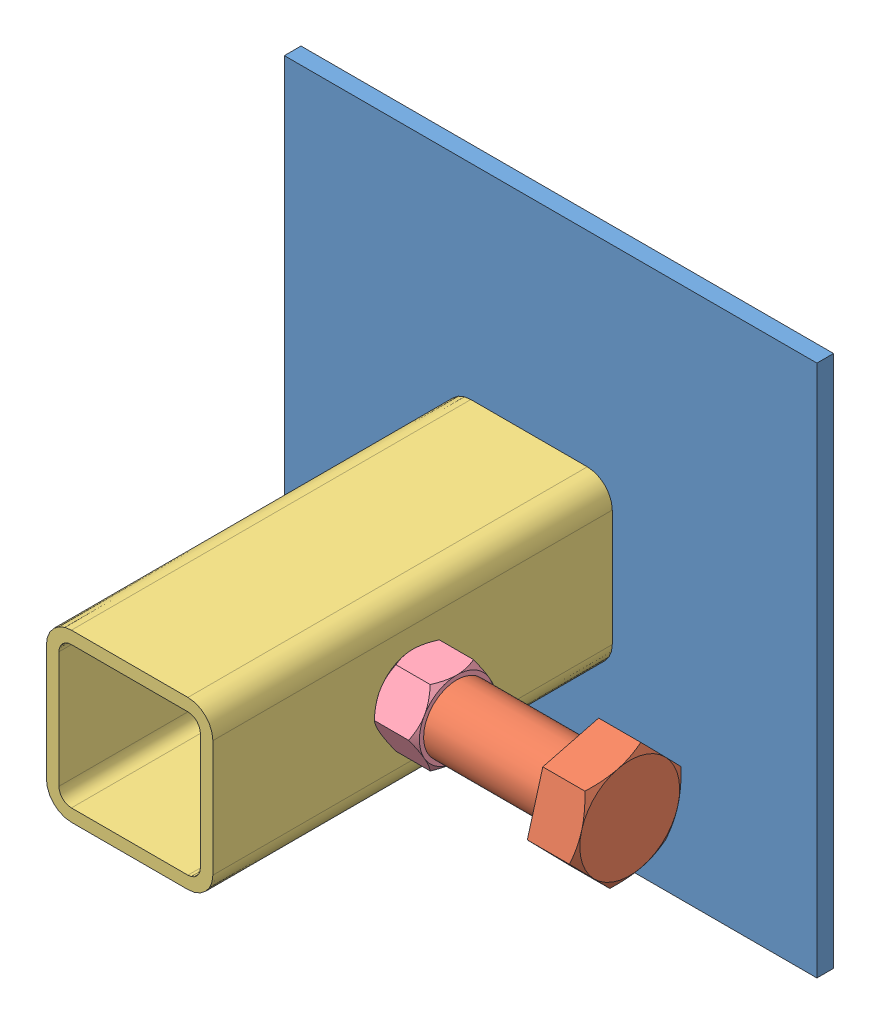
SolidWorks assembly 01-002-00-0, configuration Default. Lengths in mm.
Overall size (216.22 203.2 166.98).
5 component instances, 4 part files, 3 mates.
Components (placement in the parent):
- 01-006-00-0-1: 01-006-00-0 [Default] at (-76.2 -76.2 -19.05) x (1 0 0) z (0 -1 0) size (203.2 6.35 203.2)
- hex bolt_ai_2-1: hex bolt_ai_2 [PreviewCfg] at (140.0175 25.3891 71.7332) x (-1 0 0) z (0 -0.268825 -0.963189) size (93.98 43.99 38.1)
- Leg Support Ass-1: Leg Support Ass [Default] at (22.0978 -9.1584 55.7407) x (0 -1 0) z (0 0 1) size (63.5 80.39 152.4)
  - leg_2-1: leg_2 [TS2.5x2.5x0.1875x6] at (-66.3083 -28.4478 15.9925) size (63.5 63.5 152.4)
  - hex nut_ai-1: hex nut_ai [HNUT 0.7500-10-D-C] at (-34.5474 51.9432 15.9925) x (1 0 0) z (0 1 0) size (28.57 33 16.89)
Mates (geometry in assembly coordinates):
- Distance1: distance = 69.85 mm aligned: plane of Leg Support Ass-1/leg_2-1 through (47.625 -6.35 147.9332) normal (0 -1 0); plane of 01-006-00-0-1 through (-76.2 -76.2 -12.7) normal (0 -1 0)
- Distance2: distance = 69.85 mm aligned: plane of Leg Support Ass-1/leg_2-1 through (-6.35 47.625 147.9332) normal (-1 0 0); plane of 01-006-00-0-1 through (-76.2 -76.2 -12.7) normal (-1 0 0)
- Concentric1: concentric aligned: cylinder of hex bolt_ai_2-1 through (140.0175 25.3891 71.7332) axis (1 0 0) radius 12.7; cylinder of Leg Support Ass-1/hex nut_ai-1 through (57.15 25.3891 71.7332) axis (1 0 0) radius 8.3337
